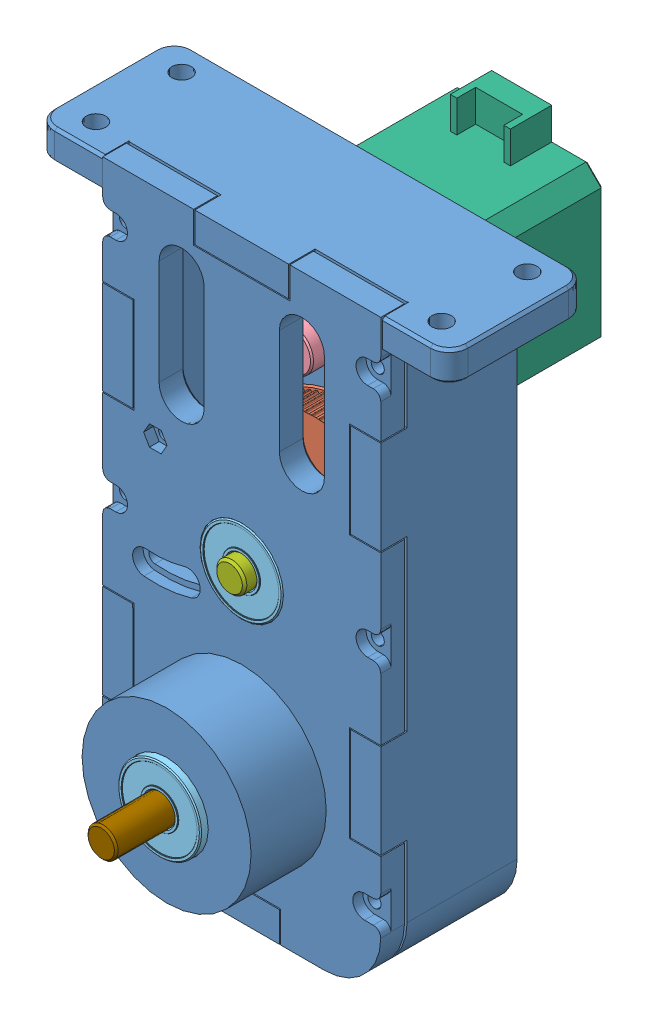
SolidWorks assembly ArmSegmentV3Assem, configuration Default. Lengths in mm.
Overall size (110 158 134.39).
13 component instances, 9 part files, 24 mates.
Components (placement in the parent):
- ArmSegmentV3-1: ArmSegmentV3 [1st Segment] at origin size (110 158 57)
- CompoundPulley-1: CompoundPulley [Default] at (0 -48 13.4) x (0.231494 -0.972836 0) z (0 0 1) size (52.13 52.13 19.6)
- ExtendedGT2_80t_TimingBeltPulley-1: ExtendedGT2_80t_TimingBeltPulley [Default] at (0 -92 23.7) x (-0.169253 -0.985573 0) z (0 0 -1) size (52.13 52.13 21.8)
- Short-Flat_16t_TimingBeltPulley-1: Short-Flat_16t_TimingBeltPulley [Default] at (0 -3.5 14.5) x (-0.923728 -0.383049 0) z (0 0 -1) size (11.39 11.39 16.5)
- 608_Bearing-1: 608_Bearing [Default] at (0 -48 5.5) size (22 22 7)
- NEMA-17_38mm-1: NEMA-17_38mm [Default] at (0 -3.5 -38) size (42.3 50.8 62)
- 608_Bearing-2: 608_Bearing [Default] at (0 -48 33.75) x (0.999953 -0.009673 0) z (0 0 1) size (22 22 7)
- 608_Bearing-3: 608_Bearing [Default] at (0 -92 1.6428) x (0.99815 -0.060807 0) z (0 0 1) size (22 22 7)
- 608_Bearing-4: 608_Bearing [Default] at (0 -92 55.5) x (0.999971 -0.007632 0) z (0 0 1) size (22 22 7)
- 8mmRod-2: 8mmRod [Default] at (0 -48 2.25) size (8 8 38)
- Idler Mount-1: Idler Mount [Default] at (-21.8824 -58.9792 30) x (0.037254 -0.999306 0) z (0 0 -1) size (41 12 11)
- 608_Bearing-5: 608_Bearing [Default] at (-21.8824 -58.9792 23.5) x (-0.809462 -0.587172 0) z (0 0 -1) size (22 22 7)
- long8mmRod-1: long8mmRod [Default] at (0 -92 -1.6072) x (0.466314 0.884619 0) z (0 0 1) size (8 8 98)
Mates (geometry in assembly coordinates):
- Coincident1: coincident anti-aligned: plane of ArmSegmentV3-1 through (0 0 0) normal (0 0 -1); plane of NEMA-17_38mm-1 through (0 -3.5 0) normal (0 0 1)
- Concentric1: concentric aligned: cylinder of ArmSegmentV3-1 through (0 -3.5 7) axis (0 0 -1) radius 11.1; cylinder of NEMA-17_38mm-1 through (0 -3.5 2) axis (0 0 -1) radius 11
- Concentric2: concentric anti-aligned: cylinder of ArmSegmentV3-1 through (15.5 -19 7) axis (0 0 -1) radius 1.8; cylinder of NEMA-17_38mm-1 through (15.5 -19 -5) axis (0 0 1) radius 1.5
- Concentric3: concentric anti-aligned: cylinder of ArmSegmentV3-1 through (0 -48 2) axis (0 0 1) radius 11.1; cylinder of 608_Bearing-1 through (0 -48 9) axis (0 0 -1) radius 11
- Coincident2: coincident aligned: plane of ArmSegmentV3-1 through (0 -48 2) normal (0 0 1); circle of 608_Bearing-1
- Concentric6: concentric aligned: cylinder of 608_Bearing-1 through (0 -48 9) axis (0 0 -1) radius 4; cylinder of 8mmRod-2 through (0 -48 40.25) axis (0 0 -1) radius 4
- Coincident5: coincident aligned: plane of 608_Bearing-1 through (0 -48 2.25) normal (0 0 -1); plane of 8mmRod-2 through (0 -48 2.25) normal (0 0 -1)
- Concentric7: concentric anti-aligned: cylinder of CompoundPulley-1 through (0 -48 19.8) axis (0 0 1) radius 4; cylinder of 8mmRod-2 through (0 -48 40.25) axis (0 0 -1) radius 4
- Coincident6: coincident anti-aligned: plane of CompoundPulley-1 through (0 -48 9) normal (0 0 -1); plane of 608_Bearing-1 through (0 -48 9) normal (0 0 1)
- Distance1: distance = 1.5 mm anti-aligned: plane of ExtendedGT2_80t_TimingBeltPulley-1 through (0 -92 19.3) normal (0 0 -1); plane of CompoundPulley-1 through (0 -48 17.8) normal (0 0 1)
- Concentric9: concentric aligned: cylinder of Idler Mount-1 through (-21.8824 -58.9792 19) axis (0 0 1) radius 4.05; cylinder of 608_Bearing-5 through (-21.8824 -58.9792 20) axis (0 0 1) radius 4
- Coincident8: coincident anti-aligned: plane of Idler Mount-1 through (-21.8824 -58.9792 27) normal (0 0 -1); plane of 608_Bearing-5 through (-21.8824 -58.9792 27) normal (0 0 1)
- Concentric10: concentric aligned: cylinder of ArmSegmentV3-1 through (-23 -29 14.2373) axis (0 0 1) radius 1.8; cylinder of Idler Mount-1 through (-23 -29 27) axis (0 0 1) radius 1.8
- Coincident9: coincident anti-aligned: plane of ArmSegmentV3-1 through (0 0 30) normal (0 0 -1); plane of Idler Mount-1 through (-21.8824 -58.9792 30) normal (0 0 1)
- Concentric11: concentric anti-aligned: cylinder of 608_Bearing-2 through (0 -48 37.25) axis (0 0 -1) radius 11; cylinder of ArmSegmentV3-1 through (0 -48 -0.001) axis (0 0 1) radius 11.1
- Concentric12: concentric anti-aligned: cylinder of ArmSegmentV3-1 through (0 -92 52) axis (0 0 1) radius 11.1; cylinder of 608_Bearing-4 through (0 -92 59) axis (0 0 -1) radius 11
- Coincident10: coincident anti-aligned: plane of ArmSegmentV3-1 through (0 0 52) normal (0 0 1); plane of 608_Bearing-4 through (0 -92 52) normal (0 0 -1)
- Concentric13: concentric aligned: cylinder of 608_Bearing-3 through (0 -92 5.1428) axis (0 0 -1) radius 4; cylinder of long8mmRod-1 through (0 -92 96.3928) axis (0 0 -1) radius 4
- Concentric14: concentric aligned: cylinder of ExtendedGT2_80t_TimingBeltPulley-1 through (0 -92 28.1) axis (0 0 -1) radius 4; cylinder of long8mmRod-1 through (0 -92 96.3928) axis (0 0 -1) radius 4
- Concentric15: concentric aligned: cylinder of 608_Bearing-4 through (0 -92 59) axis (0 0 -1) radius 4; cylinder of long8mmRod-1 through (0 -92 96.3928) axis (0 0 -1) radius 4
- Coincident12: coincident aligned: plane of 608_Bearing-3 through (0 -92 -1.6072) normal (0 0 -1); plane of long8mmRod-1 through (0 -92 -1.6072) normal (0 0 -1)
- Concentric16: concentric aligned: cylinder of Short-Flat_16t_TimingBeltPulley-1 through (0 -3.5 19.5) axis (0 0 -1) radius 2.61; cylinder of NEMA-17_38mm-1 through (0 -3.5 24) axis (0 0 -1) radius 2.5
- Coincident13: coincident aligned: plane of Short-Flat_16t_TimingBeltPulley-1 through (0 -3.5 24) normal (0 0 1); plane of NEMA-17_38mm-1 through (0 -3.5 24) normal (0 0 1)
- Coincident14: coincident aligned: plane of ArmSegmentV3-1 through (0 0 37) normal (0 0 1); plane of 608_Bearing-2 through (0 -48 37) normal (0 0 1)
